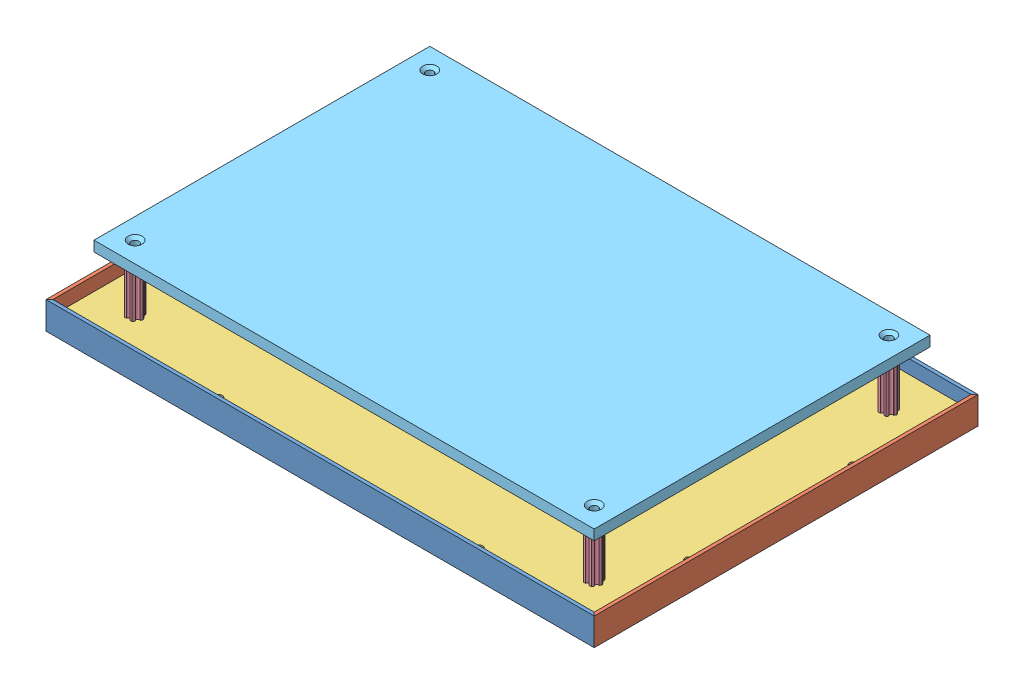
SolidWorks assembly Driver_station_v2, configuration Default. Lengths in mm.
Overall size (508 73.03 355.6).
12 component instances, 6 part files, 26 mates.
Components (placement in the parent):
- Front_and_back_angle-1: Front_and_back_angle [Default] at (455.2043 275.5666 355.3845) size (508 25.4 25.4)
- Left_and_right_angle-1: Left_and_right_angle [Default] at (-52.7957 275.5666 355.3845) x (0 0 -1) z (1 0 0) size (355.6 25.4 25.4)
- Front_and_back_angle-2: Front_and_back_angle [Default] at (-52.7957 275.5666 710.9845) x (-1 0 0) z (0 0 -1) size (508 25.4 25.4)
- Left_and_right_angle-2: Left_and_right_angle [Default] at (455.2043 275.5666 710.9845) x (0 0 1) z (-1 0 0) size (355.6 25.4 25.4)
- Bottom_acrylic-1: Bottom_acrylic [Default] at (-58.1089 278.7416 358.5595) size (501.65 9.53 349.25)
- Churro-1: Churro [Default] at (413.9293 288.2666 669.7095) x (1 0 0) z (0 -1 0) size (14.66 12.7 50.8)
- Churro-2: Churro [Default] at (413.9293 288.2666 396.6595) x (1 0 0) z (0 -1 0) size (14.66 12.7 50.8)
- Churro-3: Churro [Default] at (-11.5207 288.2666 396.6595) x (1 0 0) z (0 -1 0) size (14.66 12.7 50.8)
- Churro-4: Churro [Default] at (-11.5207 339.0666 669.7095) x (1 0 0) z (0 1 0) size (14.66 12.7 50.8)
- Top_acrylic-1: Top_acrylic [Default] at (-30.5707 339.0666 377.6095) size (463.55 9.53 311.15)
- Joystick_placeholder-1: Joystick_placeholder [Default] at (172.6293 348.5916 450.6345) x (0 0 1) z (-1 0 0) size (165.1 177.8 165.1) (hidden)
- Joystick_placeholder-2: Joystick_placeholder [Default] at (229.7793 348.5916 615.7345) x (0 0 -1) z (1 0 0) size (165.1 177.8 165.1) (hidden)
Mates (geometry in assembly coordinates):
- Coincident1: coincident anti-aligned: plane of Front_and_back_angle-1 through (-52.7957 197.8987 355.3845) normal (-0.707107 0 0.707107); plane of Left_and_right_angle-1 through (-52.7957 177.2986 355.3845) normal (0.707107 0 -0.707107)
- Coincident2: coincident aligned: line of Front_and_back_angle-1 through (-52.7957 300.9666 355.3845) axis (0 -1 0); line of Left_and_right_angle-1 through (-52.7957 300.9666 355.3845) axis (0 -1 0)
- Coincident3: coincident anti-aligned: line of Front_and_back_angle-1 through (-49.6207 278.7416 358.5595) axis (0.707107 0 0.707107); line of Left_and_right_angle-1 through (-27.3957 278.7416 380.7845) axis (-0.707107 0 -0.707107)
- Coincident4: coincident anti-aligned: plane of Left_and_right_angle-1 through (-52.7957 177.2986 710.9845) normal (0.707107 0 0.707107); plane of Front_and_back_angle-2 through (-52.7957 161.043 710.9845) normal (-0.707107 0 -0.707107)
- Coincident7: coincident aligned: line of Left_and_right_angle-1 through (-52.7957 300.9666 710.9845) axis (0 -1 0); line of Front_and_back_angle-2 through (-52.7957 300.9666 710.9845) axis (0 -1 0)
- Coincident10: coincident anti-aligned: line of Left_and_right_angle-1 through (-49.6207 278.7416 707.8095) axis (0.707107 0 -0.707107); line of Front_and_back_angle-2 through (-27.3957 278.7416 685.5845) axis (-0.707107 0 0.707107)
- Coincident11: coincident anti-aligned: plane of Front_and_back_angle-1 through (455.2043 161.043 355.3845) normal (0.707107 0 0.707107); plane of Left_and_right_angle-2 through (455.2043 177.2986 355.3845) normal (-0.707107 0 -0.707107)
- Coincident12: coincident anti-aligned: line of Front_and_back_angle-1 through (429.8043 278.7416 380.7845) axis (0.707107 0 -0.707107); line of Left_and_right_angle-2 through (452.0293 278.7416 358.5595) axis (-0.707107 0 0.707107)
- Coincident13: coincident aligned: line of Front_and_back_angle-1 through (455.2043 300.9666 355.3845) axis (0 -1 0); line of Left_and_right_angle-2 through (455.2043 300.9666 355.3845) axis (0 -1 0)
- Coincident14: coincident anti-aligned: plane of Left_and_right_angle-1 through (-52.7957 278.7416 355.3845) normal (0 1 0); plane of Bottom_acrylic-1 through (-58.1089 278.7416 358.5595) normal (0 -1 0)
- Coincident15: coincident anti-aligned: plane of Front_and_back_angle-1 through (-52.7957 300.9666 358.5595) normal (0 0 1); plane of Bottom_acrylic-1 through (-49.6207 288.2666 358.5595) normal (0 0 -1)
- Coincident16: coincident anti-aligned: plane of Left_and_right_angle-1 through (-49.6207 300.9666 710.9845) normal (1 0 0); plane of Bottom_acrylic-1 through (-49.6207 288.2666 358.5595) normal (-1 0 0)
- Concentric1: concentric: point of Bottom_acrylic-1; cylinder of Churro-1 through (413.9293 339.0666 669.7095) axis (0 -1 0) radius 2.9337
- Coincident18: coincident anti-aligned: plane of Bottom_acrylic-1 through (-58.1089 288.2666 358.5595) normal (0 1 0); plane of Churro-1 through (419.4286 288.2666 666.5345) normal (0 -1 0)
- Concentric2: concentric: point of Bottom_acrylic-1; cylinder of Churro-2 through (413.9293 339.0666 396.6595) axis (0 -1 0) radius 2.9337
- Coincident20: coincident anti-aligned: plane of Bottom_acrylic-1 through (-58.1089 288.2666 358.5595) normal (0 1 0); plane of Churro-2 through (419.4286 288.2666 393.4845) normal (0 -1 0)
- Concentric3: concentric: point of Bottom_acrylic-1; cylinder of Churro-3 through (-11.5207 339.0666 396.6595) axis (0 -1 0) radius 2.9337
- Coincident22: coincident anti-aligned: plane of Bottom_acrylic-1 through (-58.1089 288.2666 358.5595) normal (0 1 0); plane of Churro-3 through (-6.0214 288.2666 393.4845) normal (0 -1 0)
- Concentric4: concentric: point of Bottom_acrylic-1; cylinder of Churro-4 through (-11.5207 288.2666 669.7095) axis (0 1 0) radius 2.9337
- Coincident24: coincident anti-aligned: plane of Bottom_acrylic-1 through (-58.1089 288.2666 358.5595) normal (0 1 0); plane of Churro-4 through (-6.0214 288.2666 672.8845) normal (0 -1 0)
- Concentric7: concentric anti-aligned: cylinder of Churro-1 through (413.9293 339.0666 669.7095) axis (0 -1 0) radius 2.9337; cylinder of Top_acrylic-1 through (413.9293 328.9638 669.7095) axis (0 1 0) radius 3.5719
- Coincident27: coincident anti-aligned: plane of Churro-2 through (419.4286 339.0666 393.4845) normal (0 1 0); plane of Top_acrylic-1 through (-30.5707 339.0666 377.6095) normal (0 -1 0)
- Coincident28: coincident: point of Top_acrylic-1; point of Joystick_placeholder-1
- Coincident29: coincident aligned: line of Top_acrylic-1 through (7.5293 348.5916 377.6095) axis (0 0 1); line of Joystick_placeholder-1 through (7.5293 348.5916 450.6345) axis (0 0 1)
- Coincident30: coincident: point of Top_acrylic-1; point of Joystick_placeholder-2
- Coincident31: coincident anti-aligned: line of Top_acrylic-1 through (394.8793 348.5916 377.6095) axis (0 0 1); line of Joystick_placeholder-2 through (394.8793 348.5916 615.7345) axis (0 0 -1)
